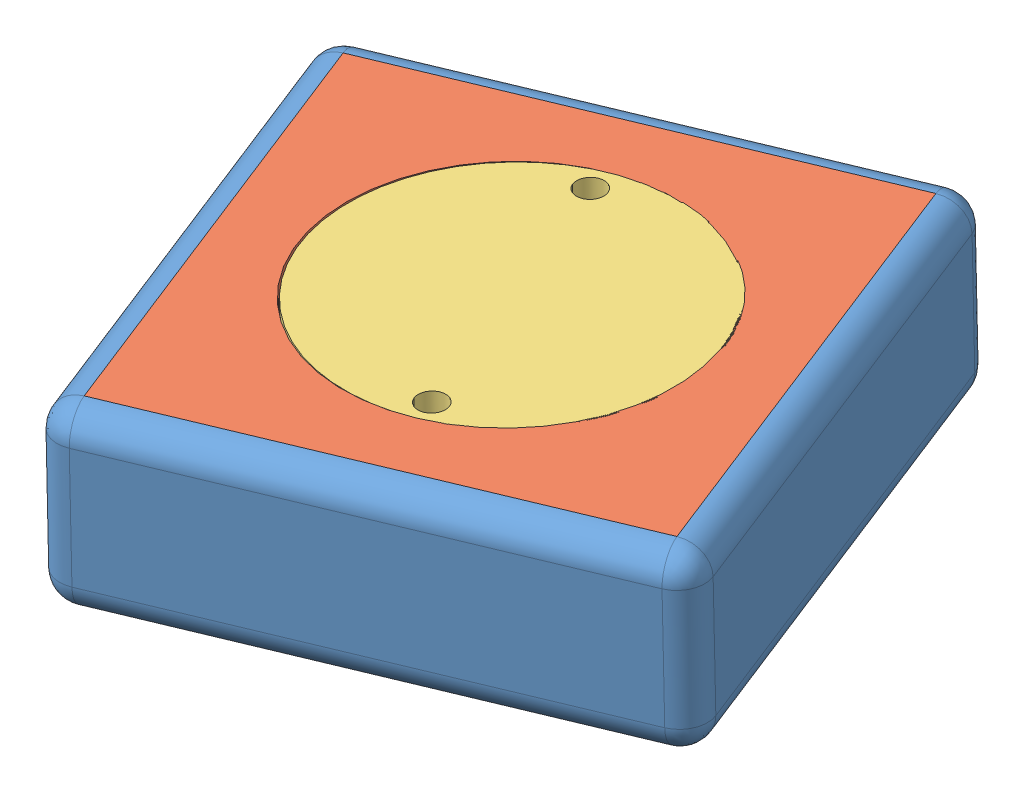
SolidWorks assembly Assem3, configuration Default. Lengths in mm.
Overall size (72.86 20.11 72.71).
3 component instances, 3 part files, 4 mates.
Components (placement in the parent):
- Part4-1: Part4 [Default] at (28.5771 -5.3532 -9.3625) x (0.364986 -0.001312 0.931012) z (0.015189 -0.999858 -0.007363) size (56 56 19.1)
- Part5-1: Part5 [Default] at (7.2233 -12.3522 14.2278) x (0.930889 0.016828 -0.364914) z (0.364986 -0.001312 0.931012) size (50 6.5 50)
- Part6-1: Part6 [Default] at (3.0542 -8.9576 20.0082) x (-0.930584 -0.016829 0.365691) z (-0.365763 0.001297 -0.930707) size (36 3 36)
Mates (geometry in assembly coordinates):
- Coincident1: coincident: line of Part4-1 through (-19.6651 -6.249 12.771) axis (0.364986 -0.001312 0.931012); line of Part5-1 through (-19.6651 -6.249 12.771) axis (0.364986 -0.001312 0.931012)
- Coincident2: coincident: line of Part4-1 through (-1.4158 -6.3146 59.3216) axis (0.930889 0.016828 -0.364914); line of Part5-1 through (-1.4158 -6.3146 59.3216) axis (0.930889 0.016828 -0.364914)
- Coincident4: coincident: circle of Part5-1; cylinder of Part6-1 through (7.1201 -8.8404 12.4706) axis (-0.015189 0.999858 0.007363) radius 1.5
- Coincident5: coincident: plane of Part5-1 through (7.1246 -5.8532 14.2757) normal (-0.015189 0.999858 0.007363); circle of Part6-1
